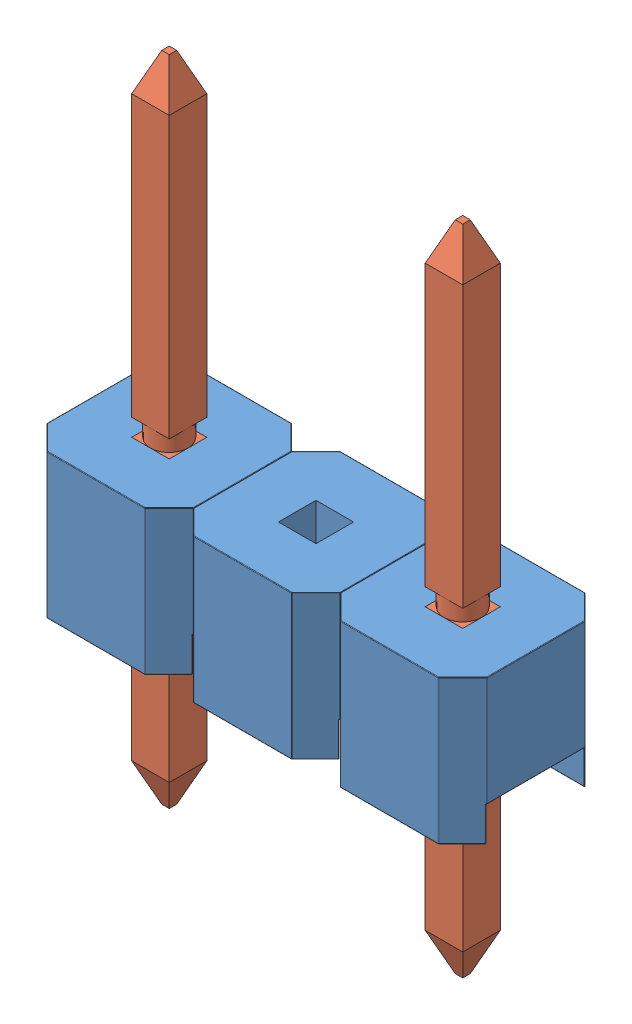
SolidWorks assembly C00022, configuration Pin Header Male 11mm 2.54mm-PITCH 1x03. Lengths in mm.
Overall size (7.62 11.3 2.54).
6 component instances, 2 part files, 4 mates.
Components (placement in the parent):
- C00022-PART-01-1: C00022-PART-01 [Default] at origin
- C00022-PART-02-1: C00022-PART-02 [Default] at (1.27 -3 -1.27)
- C00022-PART-01-2: C00022-PART-01 [Default] at (2.54 0 0)
- C00022-PART-02-2: C00022-PART-02 [Default] at (3.81 -3 -1.27) (suppressed, hidden)
- C00022-PART-01-3: C00022-PART-01 [Default] at (5.08 0 0)
- C00022-PART-02-3: C00022-PART-02 [Default] at (6.35 -3 -1.27)
Mates (geometry in assembly coordinates):
- Coincident1: coordinate: point of Base-1
- Coincident3: coincident anti-aligned: plane of Base-1 through (1.595 0 -0.945) normal (0 0 -1); plane of C00017-PART-02-1 through (0.945 8.3 -0.945) normal (0 0 1)
- Coincident4: coincident anti-aligned: plane of Base-1 through (1.595 0 -0.945) normal (-1 0 0); plane of C00017-PART-02-1 through (1.595 8.3 -0.945) normal (1 0 0)
- Distance1: distance = 3 mm aligned: plane of Base-1 through (0 0 0) normal (0 -1 0); plane of C00017-PART-02-1 through (1.27 -3 -1.27) normal (0 -1 0)
